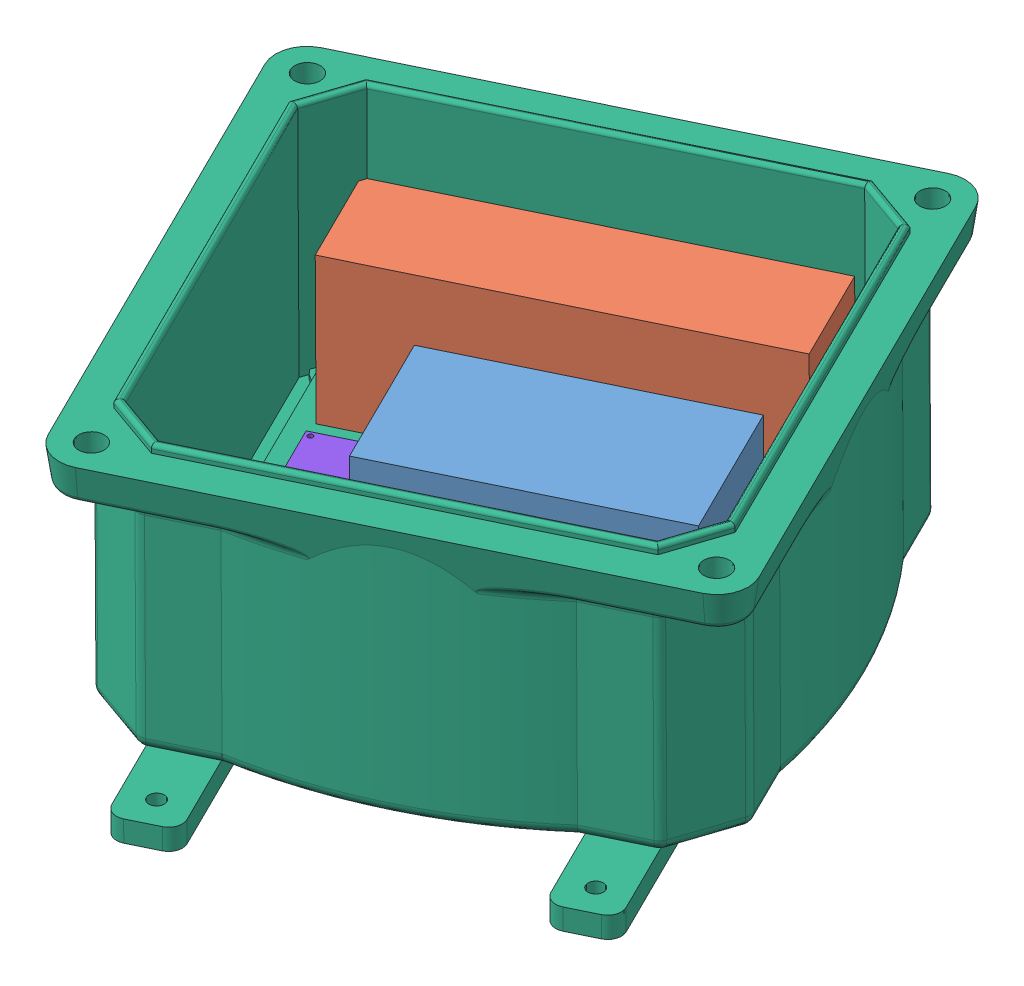
SolidWorks assembly Piponics_enlcosure, configuration Default. Lengths in mm.
Overall size (489.07 118.59 443.04).
8 component instances, 8 part files, 22 mates.
Components (placement in the parent):
- breadboard-1: breadboard [Default] at (-245.4257 26.5345 169.3086) x (0.437313 -0.015372 0.899178) z (-0.899277 0.001046 0.437379) size (57 35 106)
- Power_supply-1: Power_supply [Default] at (-274.8005 88.0038 76.7695) x (0.899277 -0.001046 -0.437379) z (-0.007664 -0.999881 -0.013366) size (150 40 60)
- relay_block-1: relay_block [Default] at (-304.3858 25.7856 259.1379) x (-0.899277 0.001046 0.437379) z (-0.437313 0.015372 -0.899178) size (78 19 55)
- RPi_case-1: RPi_case [Default] at (-384.4175 26.8472 225.6069) x (-0.437313 0.015372 -0.899178) z (0.899277 -0.001046 -0.437379) size (80 15 38)
- Terminal_block_metal-1: Terminal_block_metal [Default] at (-218.124 36.2326 251.1408) x (0.899277 -0.001046 -0.437379) z (-0.437313 0.015372 -0.899178) size (98 11 17)
- 5376K132_WATERTIGHT ENCLOSURE WITH VERSA-MOUNT SYSTEM-2: 5376K132_WATERTIGHT ENCLOSURE WITH VERSA-MOUNT SYSTEM [5376K132] at (-300.6727 5.8594 189.3585) x (-0.899277 0.001046 0.437379) z (0.007664 0.999881 0.013366) size (215.92 265.18 114.3)
- pH_board-1: pH_board [Default] at (-213.4354 40.2267 248.9288) x (0.437313 -0.015372 0.899178) z (0.899277 -0.001046 -0.437379) size (45 15 30)
- water_level_sensor_board-1: water_level_sensor_board [Default] at (-384.4579 35.3272 189.7999) x (-0.899277 0.001046 0.437379) z (0.437313 -0.015372 0.899178) size (28 8 28)
Mates (geometry in assembly coordinates):
- Coincident12: coincident anti-aligned: plane of relay_block-1 through (-304.3858 25.7856 259.1379) normal (-0.007664 -0.999881 -0.013366); plane of 5376K132_WATERTIGHT ENCLOSURE WITH VERSA-MOUNT SYSTEM-2 through (-260.9112 27.9131 75.0606) normal (0.007664 0.999881 0.013366)
- Coincident15: coincident anti-aligned: plane of relay_block-1 through (-304.3858 25.7856 259.1379) normal (-0.007664 -0.999881 -0.013366); plane of 5376K132_WATERTIGHT ENCLOSURE WITH VERSA-MOUNT SYSTEM-2 through (-260.9112 27.9131 75.0606) normal (0.007664 0.999881 0.013366)
- Parallel17: parallel anti-aligned: line of Terminal_block_metal-1 through (-317.9108 56.2314 135.0945) axis (0 0 1); line of 5376K132_WATERTIGHT ENCLOSURE WITH VERSA-MOUNT SYSTEM-2 through (-178.803 -25.6754 271.7394) axis (-1 0 0)
- Coincident29: coincident anti-aligned: plane of Power_supply-1 through (-257.7678 27.3961 111.9347) normal (-0.007664 -0.999881 -0.013366); plane of 5376K132_WATERTIGHT ENCLOSURE WITH VERSA-MOUNT SYSTEM-2 through (-260.9112 27.9131 75.0606) normal (0.007664 0.999881 0.013366)
- Coincident31: coincident anti-aligned: plane of breadboard-1 through (-245.4257 26.5345 169.3086) normal (-0.007664 -0.999881 -0.013366); plane of 5376K132_WATERTIGHT ENCLOSURE WITH VERSA-MOUNT SYSTEM-2 through (-260.9112 27.9131 75.0606) normal (0.007664 0.999881 0.013366)
- Coincident32: coincident anti-aligned: plane of relay_block-1 through (-304.3858 25.7856 259.1379) normal (-0.007664 -0.999881 -0.013366); plane of 5376K132_WATERTIGHT ENCLOSURE WITH VERSA-MOUNT SYSTEM-2 through (-260.9112 27.9131 75.0606) normal (0.007664 0.999881 0.013366)
- Perpendicular1: perpendicular: line of relay_block-1 through (-328.2923 45.6288 209.937) axis (0.437313 -0.015372 0.899178); line of 5376K132_WATERTIGHT ENCLOSURE WITH VERSA-MOUNT SYSTEM-2 through (-327.924 117.2359 305.9265) axis (0.899277 -0.001046 -0.437379)
- Coincident34: coincident anti-aligned: plane of 5376K132_WATERTIGHT ENCLOSURE WITH VERSA-MOUNT SYSTEM-2 through (-260.9112 27.9131 75.0606) normal (0.007664 0.999881 0.013366); plane of water_level_sensor_board-1 through (-384.5192 27.3281 189.693) normal (-0.007664 -0.999881 -0.013366)
- Coincident35: coincident anti-aligned: plane of 5376K132_WATERTIGHT ENCLOSURE WITH VERSA-MOUNT SYSTEM-2 through (-260.9112 27.9131 75.0606) normal (0.007664 0.999881 0.013366); plane of pH_board-1 through (-213.5504 25.2285 248.7283) normal (-0.007664 -0.999881 -0.013366)
- Parallel20: parallel anti-aligned: line of Terminal_block_metal-1 through (-218.2083 25.2339 250.9938) axis (-0.899277 0.001046 0.437379); line of 5376K132_WATERTIGHT ENCLOSURE WITH VERSA-MOUNT SYSTEM-2 through (-327.8089 118.7995 307.6628) axis (0.899277 -0.001046 -0.437379)
- Parallel18: parallel anti-aligned: line of breadboard-1 through (-340.4808 61.6412 216.1386) axis (0.899277 -0.001046 -0.437379); line of Power_supply-1 through (-257.308 87.3889 112.7367) axis (-0.899277 0.001046 0.437379)
- Coincident41: coincident anti-aligned: plane of Terminal_block_metal-1 through (-218.2083 25.2339 250.9938) normal (-0.007664 -0.999881 -0.013366); plane of 5376K132_WATERTIGHT ENCLOSURE WITH VERSA-MOUNT SYSTEM-2 through (-260.9112 27.9131 75.0606) normal (0.007664 0.999881 0.013366)
- Coincident45: coincident anti-aligned: plane of RPi_case-1 through (-384.4175 26.8472 225.6069) normal (-0.007664 -0.999881 -0.013366); plane of 5376K132_WATERTIGHT ENCLOSURE WITH VERSA-MOUNT SYSTEM-2 through (-260.9112 27.9131 75.0606) normal (0.007664 0.999881 0.013366)
- Parallel23: parallel aligned: line of RPi_case-1 through (-384.3025 41.8455 225.8074) axis (0.437313 -0.015372 0.899178); line of 5376K132_WATERTIGHT ENCLOSURE WITH VERSA-MOUNT SYSTEM-2 through (-416.5774 121.4152 162.8877) axis (0.437313 -0.015372 0.899178)
- Coincident48: coincident anti-aligned: plane of breadboard-1 through (-270.0843 62.4065 118.5233) normal (-0.437313 0.015372 -0.899178); plane of Power_supply-1 through (-257.308 87.3889 112.7367) normal (0.437313 -0.015372 0.899178)
- Coincident49: coincident anti-aligned: plane of Power_supply-1 through (-274.8005 88.0038 76.7695) normal (-0.437313 0.015372 -0.899178); plane of 5376K132_WATERTIGHT ENCLOSURE WITH VERSA-MOUNT SYSTEM-2 through (-274.468 -242.0653 70.9651) normal (0.437313 -0.015372 0.899178)
- Coincident50: coincident anti-aligned: plane of breadboard-1 through (-245.1575 61.5303 169.7765) normal (0.437313 -0.015372 0.899178); plane of relay_block-1 through (-328.2923 45.6288 209.937) normal (-0.437313 0.015372 -0.899178)
- Parallel25: parallel anti-aligned: line of 5376K132_WATERTIGHT ENCLOSURE WITH VERSA-MOUNT SYSTEM-2 through (-416.5774 121.4152 162.8877) axis (0.437313 -0.015372 0.899178); line of water_level_sensor_board-1 through (-372.2131 34.8967 214.9769) axis (-0.437313 0.015372 -0.899178)
- Coincident52: coincident anti-aligned: plane of 5376K132_WATERTIGHT ENCLOSURE WITH VERSA-MOUNT SYSTEM-2 through (-330.6982 -244.7105 301.0881) normal (-0.437313 0.015372 -0.899178); plane of pH_board-1 through (-213.5504 25.2285 248.7283) normal (0.437313 -0.015372 0.899178)
- Coincident56: coincident anti-aligned: plane of Terminal_block_metal-1 through (-218.2083 25.2339 250.9938) normal (0.437313 -0.015372 0.899178); plane of 5376K132_WATERTIGHT ENCLOSURE WITH VERSA-MOUNT SYSTEM-2 through (-330.6982 -244.7105 301.0881) normal (-0.437313 0.015372 -0.899178)
- Coincident57: coincident anti-aligned: plane of breadboard-1 through (-340.4808 61.6412 216.1386) normal (-0.899277 0.001046 0.437379); plane of water_level_sensor_board-1 through (-359.3394 27.2988 177.4464) normal (0.899277 -0.001046 -0.437379)
- Coincident58: coincident anti-aligned: plane of RPi_case-1 through (-384.3025 41.8455 225.8074) normal (-0.899277 0.001046 0.437379); plane of 5376K132_WATERTIGHT ENCLOSURE WITH VERSA-MOUNT SYSTEM-2 through (-417.6486 -242.1303 157.925) normal (0.899277 -0.001046 -0.437379)
